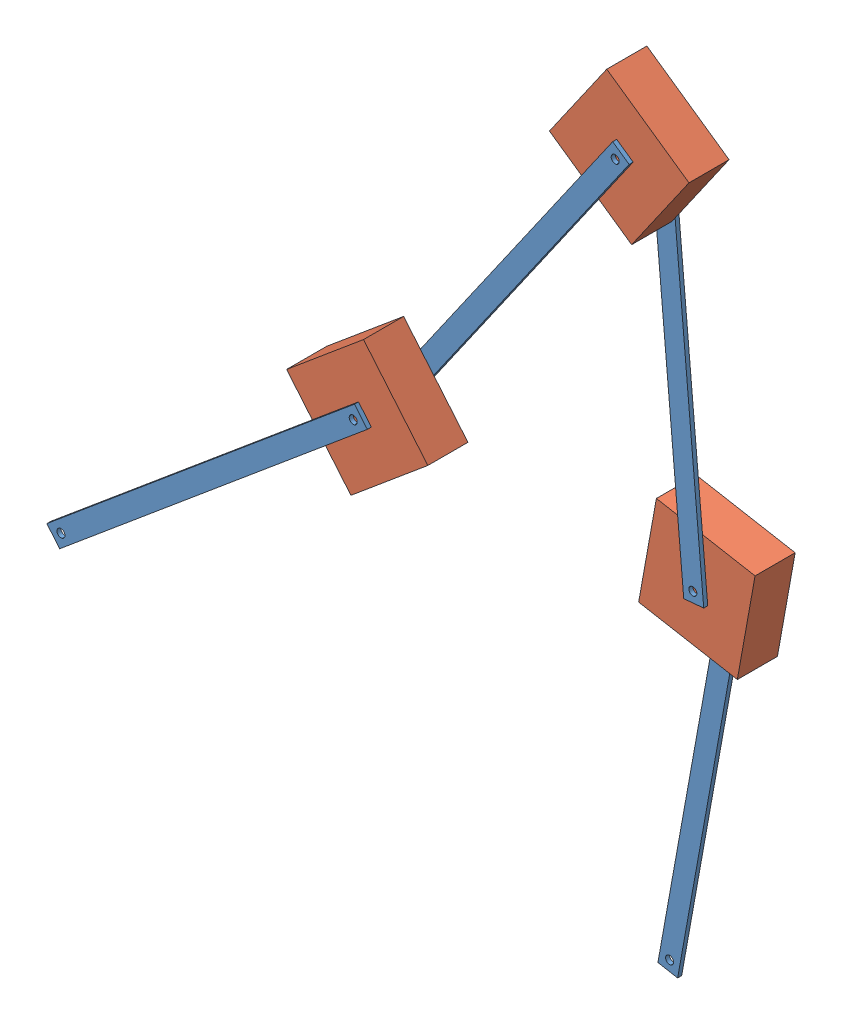
SolidWorks assembly 4link, configuration Default. Lengths in mm.
Overall size (307.23 416.88 68).
7 component instances, 2 part files, 16 mates.
Components (placement in the parent):
- pend-1: pend [Default] at (-38.4613 202.0352 161.1333) x (0.641459 -0.767157 0) z (0 0 1) size (10 200 2)
- pend-2: pend [Default] at (88.7504 340.9037 139.1333) x (0.820314 -0.571913 0) z (0 0 1) size (10 200 2)
- pend-3: pend [Default] at (151.4496 324.2027 117.1333) x (-0.996114 -0.088078 0) z (0 0 1) size (10 200 2)
- pend-4: pend [Default] at (143.0085 136.0707 95.1333) x (0.984223 -0.176932 0) z (0 0 1) size (10 200 2)
- mass-1: mass [Default] at (34.4187 262.9738 141.1333) x (0.767157 0.641459 0) z (0 0 1) size (50 50 20)
- mass-2: mass [Default] at (143.0822 418.8335 119.1333) x (0.820314 -0.571913 0) z (0 0 1) size (50 50 20)
- mass-3: mass [Default] at (159.817 229.5719 97.1333) x (-0.176932 -0.984223 0) z (0 0 1) size (50 50 20)
Mates (geometry in assembly coordinates):
- Concentric1: concentric: cylinder of pend-1 through (34.4187 262.9738 163.1333) axis (0 0 -1) radius 2; cylinder of mass-1 through (34.4187 262.9738 161.1333) axis (0 0 -1) radius 2
- Coincident1: coincident: plane of pend-1 through (-38.4613 202.0352 161.1333) normal (0 0 -1); plane of mass-1 through (34.4187 262.9738 161.1333) normal (0 0 1)
- Coincident2: coincident: plane of pend-2 through (88.7504 340.9037 141.1333) normal (0 0 1); plane of mass-1 through (34.4187 262.9738 141.1333) normal (0 0 -1)
- Concentric2: concentric: cylinder of pend-2 through (34.4187 262.9738 141.1333) axis (0 0 -1) radius 2; cylinder of mass-1 through (34.4187 262.9738 161.1333) axis (0 0 -1) radius 2
- Concentric3: concentric: cylinder of pend-2 through (143.0822 418.8335 141.1333) axis (0 0 -1) radius 2; cylinder of pend-3 through (143.0822 418.8335 119.1333) axis (0 0 -1) radius 2
- Concentric4: concentric: cylinder of pend-2 through (143.0822 418.8335 141.1333) axis (0 0 -1) radius 2; cylinder of mass-2 through (143.0822 418.8335 139.1333) axis (0 0 -1) radius 2
- Coincident3: coincident: plane of pend-2 through (88.7504 340.9037 139.1333) normal (0 0 -1); plane of mass-2 through (143.0822 418.8335 139.1333) normal (0 0 1)
- Concentric5: concentric: cylinder of pend-3 through (143.0822 418.8335 119.1333) axis (0 0 -1) radius 2; cylinder of mass-2 through (143.0822 418.8335 139.1333) axis (0 0 -1) radius 2
- Coincident4: coincident: plane of pend-3 through (151.4496 324.2027 119.1333) normal (0 0 1); plane of mass-2 through (143.0822 418.8335 119.1333) normal (0 0 -1)
- Concentric6: concentric: cylinder of pend-4 through (159.817 229.5719 97.1333) axis (0 0 -1) radius 2; cylinder of mass-3 through (159.817 229.5719 117.1333) axis (0 0 -1) radius 2
- Concentric7: concentric: cylinder of pend-3 through (159.817 229.5719 119.1333) axis (0 0 -1) radius 2; cylinder of mass-3 through (159.817 229.5719 117.1333) axis (0 0 -1) radius 2
- Coincident7: coincident: plane of pend-3 through (151.4496 324.2027 117.1333) normal (0 0 -1); plane of mass-3 through (159.817 229.5719 117.1333) normal (0 0 1)
- Coincident8: coincident: plane of pend-4 through (143.0085 136.0707 97.1333) normal (0 0 1); plane of mass-3 through (159.817 229.5719 97.1333) normal (0 0 -1)
- Parallel1: parallel: plane of pend-1 through (35.0472 270.0169 163.1333) normal (-0.641459 0.767157 0); plane of mass-1 through (-0.7967 266.1163 161.1333) normal (-0.641459 0.767157 0)
- Parallel2: parallel: plane of pend-4 through (155.7806 235.3777 97.1333) normal (-0.984223 0.176932 0); plane of mass-3 through (139.6347 258.6008 117.1333) normal (-0.984223 0.176932 0)
- Parallel3: parallel: plane of pend-2 through (141.8402 425.7946 141.1333) normal (-0.820314 0.571913 0); plane of mass-2 through (136.8722 453.6392 139.1333) normal (-0.820314 0.571913 0)
